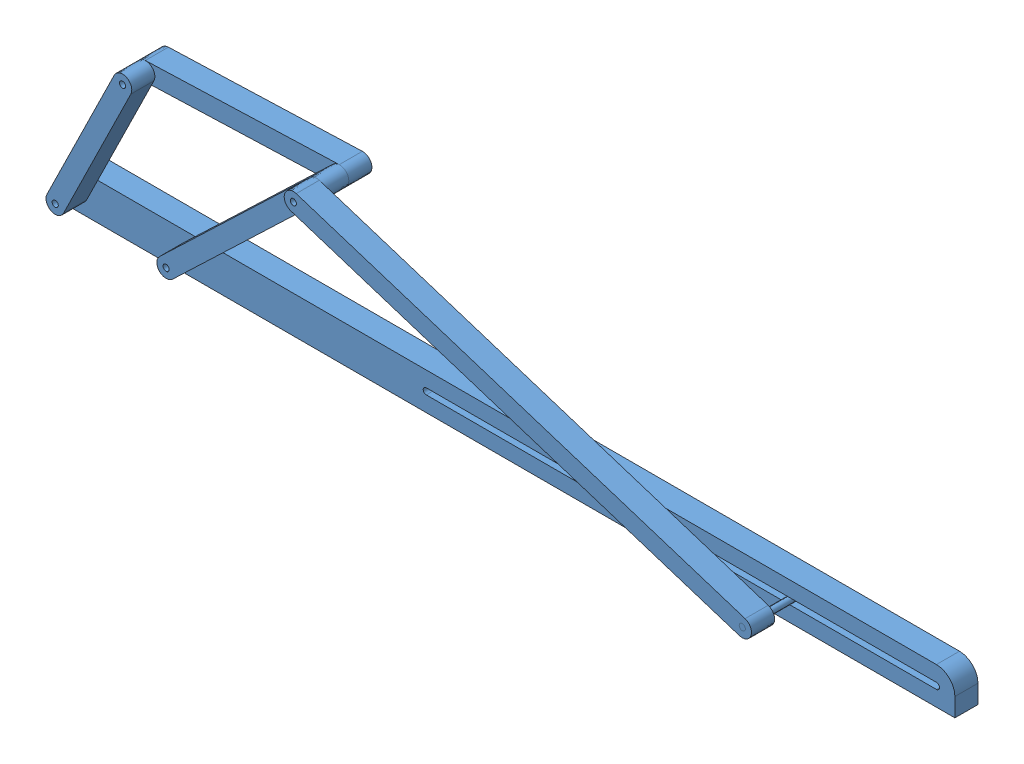
SolidWorks assembly Ensamble_Cuatro_Barras, configuration Default. Lengths in mm.
Overall size (193.72 37.21 15).
6 component instances, 1 part files, 11 mates.
Components (placement in the parent):
- Cuatro_Barras-1: Cuatro_Barras [Soporte] at (-12.5934 111.0737 186.6926) size (193.7 32.89 5)
- Cuatro_Barras-3: Cuatro_Barras [Eslabon A] at (-12.5934 111.0737 186.6926) x (0.997797 0.066334 0) z (0 0 1) size (20.5 32.58 5)
- Cuatro_Barras-4: Cuatro_Barras [Eslabon B] at (-13.7328 111.6621 181.6926) x (0.999621 0.027519 0) z (0 0 1) size (46 4.31 5)
- Cuatro_Barras-5: Cuatro_Barras [Eslabon C] at (-12.5424 109.5094 186.6926) x (0.997873 0.06518 0) z (0 0 1) size (38.5 32.89 5)
- Cuatro_Barras-6: Cuatro_Barras [Eslabon E] at (-15.1835 114.5805 191.6926) x (0.999748 -0.022433 0) z (0 0 1) size (101.82 32.89 5)
- Cuatro_Barras-7: Cuatro_Barras [PIN] at (-15.2229 111.0737 191.6926) size (1.33 1.33 15)
Mates (geometry in assembly coordinates):
- Coincidente1: coincident anti-aligned: plane of Cuatro_Barras-1 through (-12.5934 111.0737 186.6926) normal (0 0 1); plane of Cuatro_Barras-3 through (-12.5934 111.0737 186.6926) normal (0 0 -1)
- Coincidente2: coincident anti-aligned: plane of Cuatro_Barras-1 through (-12.5934 111.0737 186.6926) normal (0 0 1); plane of Cuatro_Barras-5 through (11.4066 111.0737 186.6926) normal (0 0 -1)
- Coincidente3: coincident anti-aligned: plane of Cuatro_Barras-3 through (-12.5934 111.0737 186.6926) normal (0 0 -1); plane of Cuatro_Barras-4 through (1.9745 140.6841 186.6926) normal (0 0 1)
- Concéntrica1: concentric aligned: circle of Cuatro_Barras-1; circle of Cuatro_Barras-3
- Concéntrica2: concentric aligned: circle of Cuatro_Barras-3; circle of Cuatro_Barras-4
- Concéntrica3: concentric aligned: circle of Cuatro_Barras-1; circle of Cuatro_Barras-5
- Concéntrica4: concentric aligned: circle of Cuatro_Barras-4; circle of Cuatro_Barras-5
- Concéntrica5: concentric aligned: circle of Cuatro_Barras-5; circle of Cuatro_Barras-6
- Coincidente5: coincident anti-aligned: plane of Cuatro_Barras-5 through (11.4066 111.0737 191.6926) normal (0 0 1); plane of Cuatro_Barras-6 through (43.9488 142.1544 191.6926) normal (0 0 -1)
- Tangente1: tangent: plane of Cuatro_Barras-1 through (62.7066 110.4087 181.6926) normal (0 1 0); circle of Cuatro_Barras-6
- Coincidente7: coincident aligned: circle of Cuatro_Barras-6; circle of Cuatro_Barras-7
